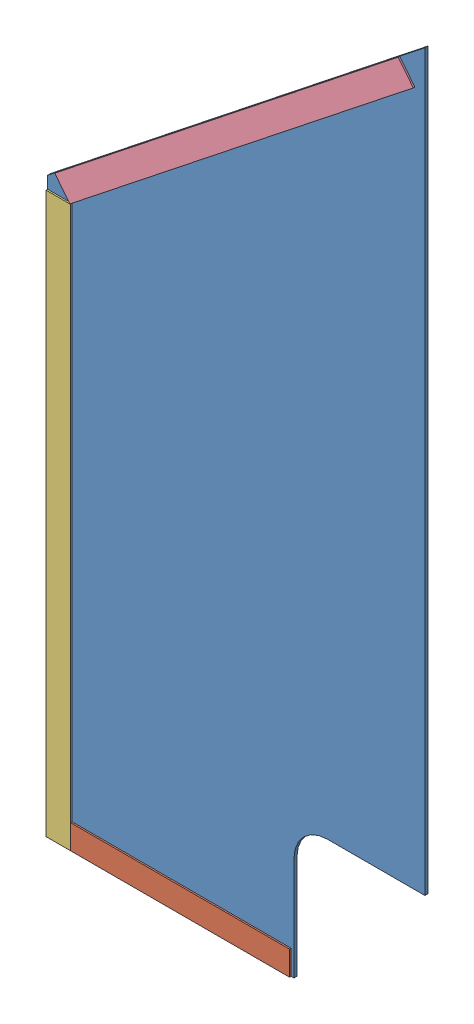
SolidWorks assembly GE-19089, configuration Default. Lengths in mm.
Overall size (393.7 908.94 4.76).
4 component instances, 4 part files, 9 mates.
Components (placement in the parent):
- GE-19089-1: GE-19089 [GE-19089] at origin size (393.7 908.94 3.17)
- Loop_1_9-1: Loop_1_9 [Default] at (-368.3 25.4 4.7625) x (1 0 0) z (0 1 0) size (228.6 1.59 25.4)
- Loop_1_23-1: Loop_1_23 [Default] at (-381 292.1 4.7625) x (0 -1 0) z (0 0 -1) size (584.2 25.4 1.59)
- Loop_1_18-1: Loop_1_18 [Default] at (-368.8314 584.2 3.175) x (0.783693 0.621148 0) z (0.621148 -0.783693 0) size (457.2 1.59 25.4)
Mates (geometry in assembly coordinates):
- Coincident1: coincident: plane of GE-19089-1 through (0 0 3.175) normal (0 0 1); plane of Loop_1_23-1 through (-381 292.1 3.175) normal (0 0 -1)
- Coincident2: coincident: plane of GE-19089-1 through (0 0 3.175) normal (0 0 1); plane of Loop_1_9-1 through (-368.3 25.4 3.175) normal (0 0 -1)
- Coincident5: coincident: plane of GE-19089-1 through (-393.7 0 3.175) normal (-1 0 0); plane of Loop_1_23-1 through (-393.7 584.2 3.175) normal (-1 0 0)
- Coincident6: coincident: plane of GE-19089-1 through (0 0 3.175) normal (0 -1 0); plane of Loop_1_23-1 through (-393.7 0 3.175) normal (0 -1 0)
- Coincident7: coincident: plane of GE-19089-1 through (0 0 3.175) normal (0 -1 0); plane of Loop_1_9-1 through (-368.3 0 3.175) normal (0 -1 0)
- Coincident8: coincident: plane of assembly; plane of assembly; plane of Loop_1_9-1 through (-368.3 25.4 3.175) normal (-1 0 0); plane of Loop_1_23-1 through (-368.3 584.2 3.175) normal (1 0 0)
- Coincident11: coincident: plane of GE-19089-1 through (0 0 3.175) normal (0 0 1); plane of Loop_1_18-1 through (-368.8314 584.2 3.175) normal (0 0 -1)
- Coincident12: coincident: plane of GE-19089-1 through (-393.7 596.9 3.175) normal (-0.621148 0.783693 0); plane of Loop_1_18-1 through (-384.6085 604.1058 4.7625) normal (-0.621148 0.783693 0)
- Coincident13: coincident: plane of assembly; point of assembly; plane of Loop_1_23-1 through (-393.7 584.2 3.175) normal (0 1 0); point of Loop_1_18-1
